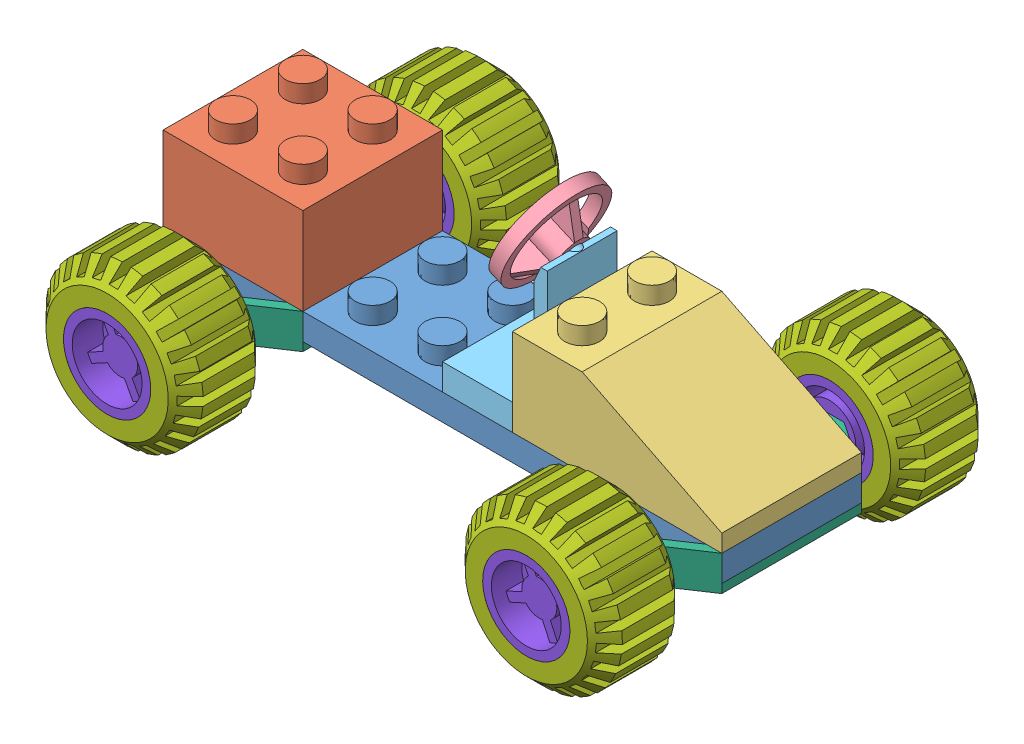
SolidWorks assembly auto, configuration Default. Lengths in mm.
Overall size (72.22 35.79 44.77).
21 component instances, 9 part files, 19 mates.
Components (placement in the parent):
- Bottom brick-1: Bottom brick [Default] at (25.9279 30.5128 50.0105) size (64 5 16)
- Back brick-1: Back brick [Default] at (-6.0721 33.5128 42.0105) size (16 12 16)
- Front brick-1: Front brick [Default] at (78.7803 48.6261 58.0105) x (0 0 -1) z (1 0 0) size (16 12 24)
- Steering wheel assembly-1: Steering wheel assembly [Default] at (36.7202 36.6458 44.703) x (0 0 1) z (-0.916157 0.400819 0) size (16 20.7 13.6)
  - Steering wheel-1: Steering wheel [Default] at (5.3075 7.6005 7.601) size (11.8 11.8 3.5)
  - Part7^Steering wheel assembly-1: Part7^Steering wheel assembly [Default] at origin (virtual)
  - Steering base-1: Steering base [Default] at (5.3075 -5.5928 4.9671) x (1 0 0) z (0 -0.400819 0.916157) size (16 15.65 8)
- Chassis-2: Chassis [Default] at (49.9279 29.5128 50.0105) x (0 0 -1) z (1 0 0) size (40 4 16)
- Chassis-3: Chassis [Default] at (1.9279 29.5128 50.0105) x (0 0 1) z (-1 0 0) size (40 4 16)
- Tire assembly-1: Tire assembly [klein] at (-4.2062 49.1673 20.0275) x (-0.510873 -0.859656 0) z (0 0 1) size (17.97 17.97 10)
  - Tire-1: Tire [Default] at (12.043 14.2925 7.6421) size (17.97 17.97 10)
  - Wheel-1: Wheel [Default] at (12.043 14.2925 12.6421) size (10 10 10)
- Tire assembly-2: Tire assembly [klein] at (19.3219 24.6748 80.0752) x (-0.879473 -0.475948 0) z (0 0 -1) size (17.97 17.97 10)
  - Tire-1: Tire [Default] at (12.043 14.2925 7.6421) size (17.97 17.97 10)
  - Wheel-1: Wheel [Default] at (12.043 14.2925 12.6421) size (10 10 10)
- Tire assembly-3: Tire assembly [klein] at (66.8126 23.4993 80.052) x (-0.910012 -0.414582 0) z (0 0 -1) size (17.97 17.97 10)
  - Tire-1: Tire [Default] at (12.043 14.2925 7.6421) size (17.97 17.97 10)
  - Wheel-1: Wheel [Default] at (12.043 14.2925 12.6421) size (10 10 10)
- Tire assembly-4: Tire assembly [klein] at (38.1715 16.9837 20.0208) x (0.999802 0.019884 0) z (0 0 1) size (17.97 17.97 10)
  - Tire-1: Tire [Default] at (12.043 14.2925 7.6421) size (17.97 17.97 10)
  - Wheel-1: Wheel [Default] at (12.043 14.2925 12.6421) size (10 10 10)
Mates (geometry in assembly coordinates):
- Coincident4: coincident: plane of Back brick-1 through (-6.0721 43.5128 42.0105) normal (-1 0 0); plane of Bottom brick-1 through (-6.0721 33.5128 42.0105) normal (-1 0 0)
- Coincident6: coincident: plane of Bottom brick-1 through (25.9279 33.5128 50.0105) normal (0 1 0); plane of Back brick-1 through (-6.0721 33.5128 42.0105) normal (0 -1 0)
- Coincident8: coincident: plane of Bottom brick-1 through (-6.0721 33.5128 42.0105) normal (0 0 -1); plane of Front brick-1 through (78.7803 48.6261 42.0105) normal (0 0 -1)
- Coincident9: coincident: plane of Bottom brick-1 through (57.9279 33.5128 42.0105) normal (1 0 0); plane of Front brick-1 through (57.9279 35.5128 42.0105) normal (1 0 0)
- Coincident10: coincident: plane of Bottom brick-1 through (25.9279 33.5128 50.0105) normal (0 1 0); plane of Front brick-1 through (57.9279 33.5128 42.0105) normal (0 -1 0)
- Coincident11: coincident: plane of Bottom brick-1 through (-6.0721 33.5128 58.0105) normal (0 0 1); plane of Back brick-1 through (-6.0721 43.5128 58.0105) normal (0 0 1)
- Coincident12: coincident: plane of Bottom brick-1 through (-6.0721 33.5128 42.0105) normal (0 0 -1); plane of Steering wheel assembly-1/Steering base-1 through (33.9279 36.5128 42.0105) normal (0 0 -1)
- Coincident13: coincident: plane of Front brick-1 through (33.9279 33.5128 42.0105) normal (-1 0 0); plane of Steering wheel assembly-1/Steering base-1 through (33.9279 36.5128 42.0105) normal (1 0 0)
- Coincident14: coincident: plane of Bottom brick-1 through (25.9279 33.5128 50.0105) normal (0 1 0); plane of Steering wheel assembly-1/Steering base-1 through (29.9279 33.5128 50.0105) normal (0 -1 0)
- Coincident23: coincident: plane of Bottom brick-1 through (57.9279 33.5128 42.0105) normal (1 0 0); plane of Chassis-2 through (57.9279 30.5128 50.0105) normal (1 0 0)
- Coincident24: coincident: plane of Bottom brick-1 through (-6.0721 33.5128 58.0105) normal (0 0 1); plane of Chassis-2 through (56.1251 33.5128 58.0105) normal (0 0 -1)
- Coincident25: coincident: plane of Bottom brick-1 through (25.9279 30.5128 50.0105) normal (0 -1 0); plane of Chassis-2 through (49.9279 30.5128 50.0105) normal (0 1 0)
- Coincident26: coincident: plane of Bottom brick-1 through (-6.0721 33.5128 58.0105) normal (0 0 1); plane of Chassis-3 through (9.9279 33.5128 58.0105) normal (0 0 -1)
- Coincident27: coincident: plane of Bottom brick-1 through (-6.0721 33.5128 42.0105) normal (-1 0 0); line of Chassis-3 through (-6.0721 30.5128 42.0105) axis (0 0 1)
- Coincident28: coincident: plane of Bottom brick-1 through (25.9279 30.5128 50.0105) normal (0 -1 0); plane of Chassis-3 through (1.9279 30.5128 50.0105) normal (0 1 0)
- Concentric1: concentric: cylinder of Chassis-3 through (1.9279 31.5128 30.0105) axis (0 0 1) radius 1.5; cylinder of Tire assembly-1/Wheel-1 through (1.9279 31.5128 34.6695) axis (0 0 1) radius 1.5
- Concentric2: concentric: cylinder of Chassis-3 through (1.9279 31.5128 70.0105) axis (0 0 -1) radius 1.5; cylinder of Tire assembly-2/Wheel-1 through (1.9279 31.5128 65.4332) axis (0 0 -1) radius 1.5
- Concentric3: concentric: cylinder of Chassis-2 through (49.9279 31.5128 70.0105) axis (0 0 -1) radius 1.5; cylinder of Tire assembly-3/Wheel-1 through (49.9279 31.5128 65.41) axis (0 0 -1) radius 1.5
- Concentric4: concentric: cylinder of Chassis-2 through (49.9279 31.5128 30.0105) axis (0 0 1) radius 1.5; cylinder of Tire assembly-4/Wheel-1 through (49.9279 31.5128 34.6629) axis (0 0 1) radius 1.5
